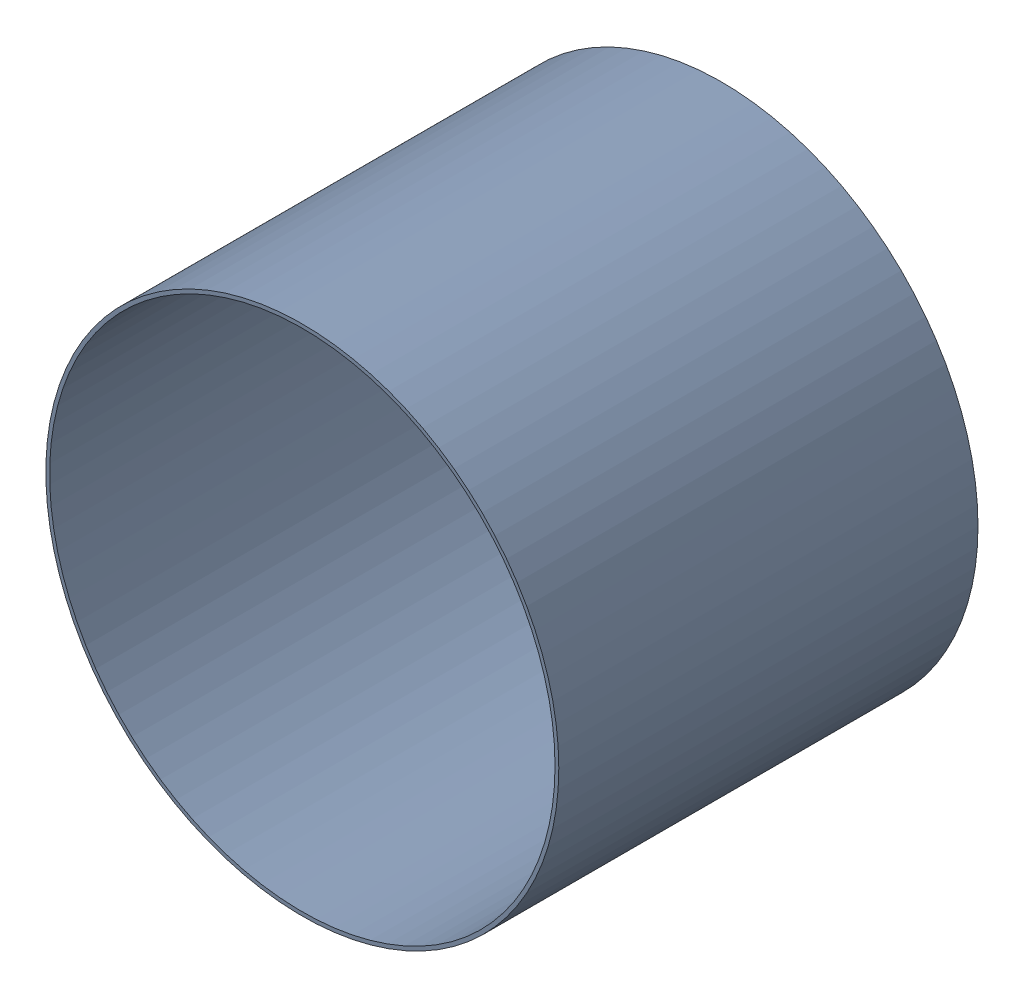
SolidWorks assembly AluminumCOPPER_PCB2x-1, configuration По умолчанию. Lengths in mm.
Overall size (3.45 3.45 2.82).
6 component instances, 2 part files, 0 mates.
Components (placement in the parent):
- Polygon Not Repour After Edit  (Top Layer-No Net) on Top Layer-1-1-1: Polygon Not Repour After Edit  (Top Layer-No Net) on Top Layer-1-1 [По умолчанию] at origin
  - Polygon Region (3 hole(s)) Top Layer-1-1-1: Polygon Region (3 hole(s)) Top Layer-1-1 [По умолчанию] at (0 0 -0.3702)
    - Polygon Region (3 hole(s)) Top Layer-Part-1-1-1: Polygon Region (3 hole(s)) Top Layer-Part-1-1 [По умолчанию] at origin (suppressed, hidden)
- Pad Free-3(60mm,64mm) on Multi-Layer-1-1: Pad Free-3(60mm,64mm) on Multi-Layer-1 [По умолчанию] at origin size (3.45 3.45 2.82)
  - Pad Hole-1-1: Pad Hole-1 [По умолчанию] at (60 64 -2.8302) size (3.45 3.45 2.82)
    - Pad Hole-Part-1-1-1: Pad Hole-Part-1-1 [По умолчанию] at origin size (3.45 3.45 2.82)
